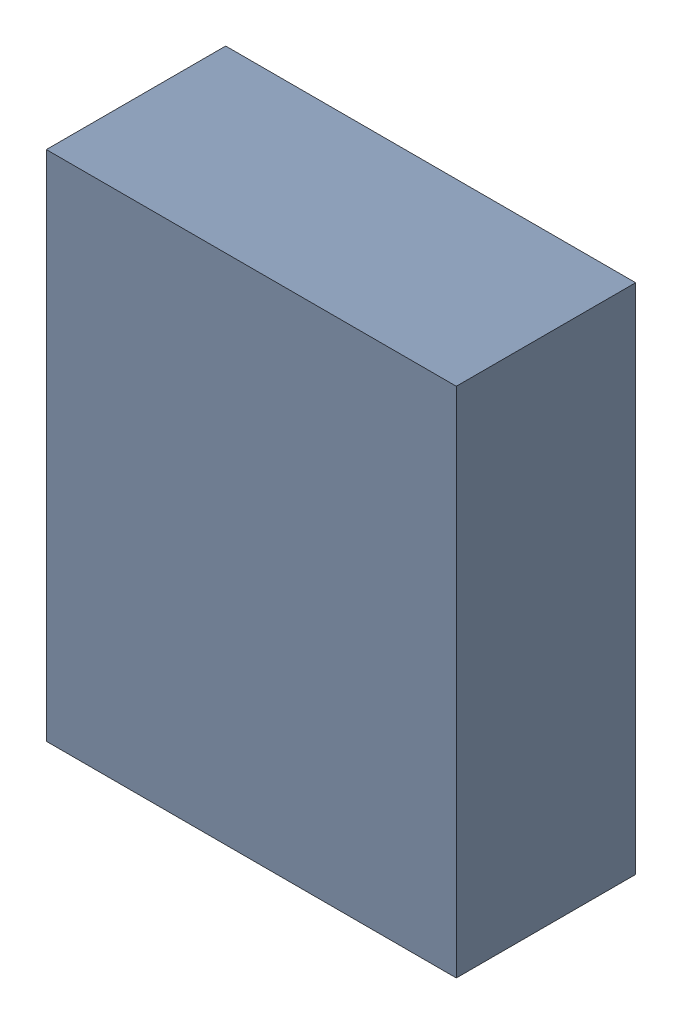
SolidWorks assembly U28, configuration ﾃﾞﾌｫﾙﾄ. Lengths in mm.
Overall size (4 5 1.75).
2 component instances, 1 part files, 0 mates.
Components (placement in the parent):
- 689262464-1: 689262464 [ﾃﾞﾌｫﾙﾄ] at (18.7325 16.8275 0) size (4 5 1.75)
  - Extruded_40-1: Extruded_40 [ﾃﾞﾌｫﾙﾄ] at origin size (4 5 1.75)
